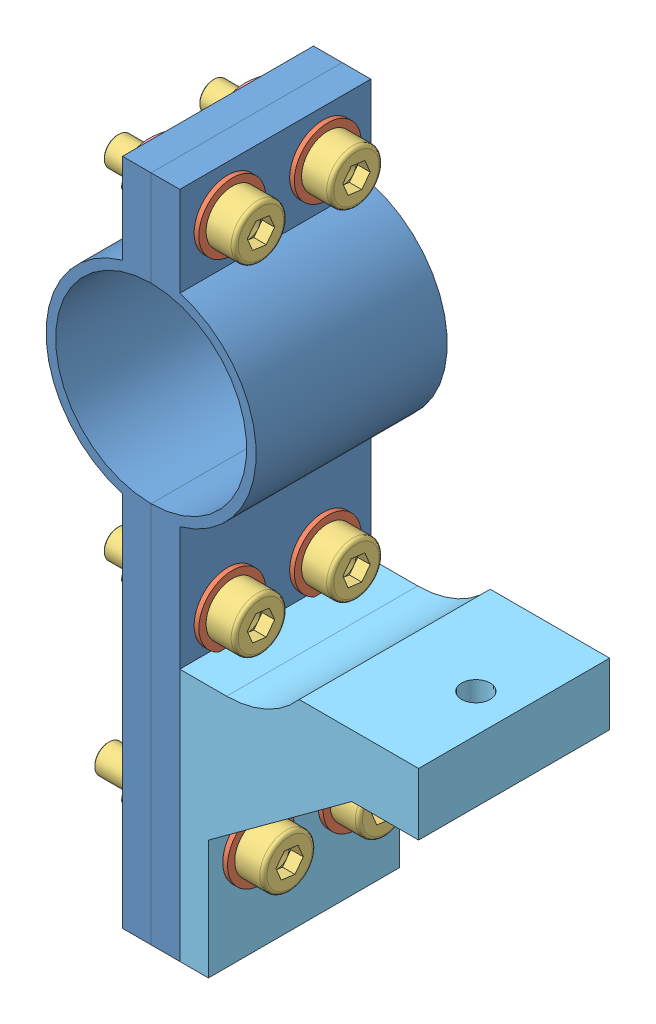
SolidWorks assembly 导轨夹具, configuration 默认. Lengths in mm.
Overall size (41 70 20).
22 component instances, 5 part files, 15 mates.
Components (placement in the parent):
- 小管夹具-1: 小管夹具 [默认] at (-12.5658 -21.1975 0) size (22 70 20)
  - 夹具-1: 夹具 [默认] at (55.615 31.0944 -10) size (11 70 20)
  - 夹具-2: 夹具 [默认] at (55.615 31.0944 10) x (-1 0 0) z (0 0 -1) size (11 70 20)
  - plain washers-n series-grade a gb-2: plain washers-n series-grade a gb [GB_FASTENER_WASHER_PWNA 3] at (59.115 46.3859 5) x (0 0 -1) z (1 0 0) size (7 7 0.5)
  - plain washers-n series-grade a gb-3: plain washers-n series-grade a gb [GB_FASTENER_WASHER_PWNA 3] at (59.115 46.3859 -5) x (0 0 -1) z (1 0 0) size (7 7 0.5)
  - plain washers-n series-grade a gb-4: plain washers-n series-grade a gb [GB_FASTENER_WASHER_PWNA 3] at (59.115 10.8029 -5) x (0 0 -1) z (1 0 0) size (7 7 0.5)
  - plain washers-n series-grade a gb-5: plain washers-n series-grade a gb [GB_FASTENER_WASHER_PWNA 3] at (59.115 10.8029 5) x (0 0 -1) z (1 0 0) size (7 7 0.5)
  - hexagon socket head cap screws gb-2: hexagon socket head cap screws gb [GB_FASTENER_SCREWS_HSHCS M3X12-N] at (62.115 10.8029 -5) x (-1 0 0) z (0 0.924225 0.381849) size (15 5.5 5.5)
  - hexagon socket head cap screws gb-3: hexagon socket head cap screws gb [GB_FASTENER_SCREWS_HSHCS M3X12-N] at (62.115 10.8029 5) x (-1 0 0) z (0 0.924225 0.381849) size (15 5.5 5.5)
  - hexagon socket head cap screws gb-4: hexagon socket head cap screws gb [GB_FASTENER_SCREWS_HSHCS M3X12-N] at (62.115 46.3859 -5) x (-1 0 0) z (0 0.924225 0.381849) size (15 5.5 5.5)
  - hexagon socket head cap screws gb-5: hexagon socket head cap screws gb [GB_FASTENER_SCREWS_HSHCS M3X12-N] at (62.115 46.3859 5) x (-1 0 0) z (0 0.924225 0.381849) size (15 5.5 5.5)
  - hex nuts, style 1-grades ab gb-2: hex nuts, style 1-grades ab gb [GB_FASTENER_NUT_SNAB1 M3-N] at (50.215 10.8029 -5) x (0 0 1) z (-1 0 0) size (6.35 5.5 2.4)
  - hex nuts, style 1-grades ab gb-3: hex nuts, style 1-grades ab gb [GB_FASTENER_NUT_SNAB1 M3-N] at (50.215 10.8029 5) x (0 0 1) z (-1 0 0) size (6.35 5.5 2.4)
  - hex nuts, style 1-grades ab gb-4: hex nuts, style 1-grades ab gb [GB_FASTENER_NUT_SNAB1 M3-N] at (50.215 46.3859 -5) x (0 0 1) z (-1 0 0) size (6.35 5.5 2.4)
  - hex nuts, style 1-grades ab gb-5: hex nuts, style 1-grades ab gb [GB_FASTENER_NUT_SNAB1 M3-N] at (50.215 46.3859 5) x (0 0 1) z (-1 0 0) size (6.35 5.5 2.4)
- 滑轨支架-1: 滑轨支架 [默认] at (49.0492 14.8969 -10) x (0 0 1) z (-1 0 0) size (20 30 27)
- plain washers-n series-grade a gb-2: plain washers-n series-grade a gb [GB_FASTENER_WASHER_PWNA 3] at (49.5492 -30.3946 5) x (0 0 -1) z (1 0 0) size (7 7 0.5)
- plain washers-n series-grade a gb-3: plain washers-n series-grade a gb [GB_FASTENER_WASHER_PWNA 3] at (49.5492 -30.3946 -5) x (0 0 -1) z (1 0 0) size (7 7 0.5)
- hexagon socket head cap screws gb-2: hexagon socket head cap screws gb [GB_FASTENER_SCREWS_HSHCS M3X16-N] at (52.5492 -30.3946 5) x (-1 0 0) z (0 0.924225 0.381849) size (19 5.5 5.5)
- hexagon socket head cap screws gb-3: hexagon socket head cap screws gb [GB_FASTENER_SCREWS_HSHCS M3X16-N] at (52.5492 -30.3946 -5) x (-1 0 0) z (0 0.924225 0.381849) size (19 5.5 5.5)
- hex nuts, style 1-grades ab gb-2: hex nuts, style 1-grades ab gb [GB_FASTENER_NUT_SNAB1 M3-N] at (37.6492 -30.3946 5) x (0 0 1) z (-1 0 0) size (6.35 5.5 2.4)
- hex nuts, style 1-grades ab gb-3: hex nuts, style 1-grades ab gb [GB_FASTENER_NUT_SNAB1 M3-N] at (37.6492 -30.3946 -5) x (0 0 1) z (-1 0 0) size (6.35 5.5 2.4)
Mates (geometry in assembly coordinates):
- 重合1: coincident anti-aligned: plane of 小管夹具-1/夹具-2 through (46.0492 9.8969 -10) normal (1 0 0); plane of 滑轨支架-1 through (46.0492 14.8969 -10) normal (-1 0 0)
- 同心1: concentric aligned: cylinder of 小管夹具-1/夹具-2 through (26.0492 -30.3946 5) axis (1 0 0) radius 1.5; cylinder of 滑轨支架-1 through (46.0492 -30.3946 5) axis (1 0 0) radius 2
- 同心2: concentric anti-aligned: cylinder of 小管夹具-1/夹具-1 through (60.0492 -30.3946 -5) axis (-1 0 0) radius 1.5; cylinder of 滑轨支架-1 through (46.0492 -30.3946 -5) axis (1 0 0) radius 2
- 同心3: concentric aligned: cylinder of 滑轨支架-1 through (46.0492 -30.3946 5) axis (1 0 0) radius 2; cylinder of plain washers-n series-grade a gb-2 through (49.0492 -30.3946 5) axis (1 0 0) radius 1.6
- 重合2: coincident anti-aligned: plane of 滑轨支架-1 through (49.0492 14.8969 -10) normal (1 0 0); plane of plain washers-n series-grade a gb-2 through (49.0492 -30.3946 5) normal (-1 0 0)
- 同心4: concentric aligned: cylinder of 滑轨支架-1 through (46.0492 -30.3946 -5) axis (1 0 0) radius 2; cylinder of plain washers-n series-grade a gb-3 through (49.0492 -30.3946 -5) axis (1 0 0) radius 1.6
- 重合3: coincident anti-aligned: plane of 滑轨支架-1 through (49.0492 14.8969 -10) normal (1 0 0); plane of plain washers-n series-grade a gb-3 through (49.0492 -30.3946 -5) normal (-1 0 0)
- 同心5: concentric aligned: cylinder of 滑轨支架-1 through (46.0492 -30.3946 5) axis (1 0 0) radius 2; cylinder of hexagon socket head cap screws gb-2 through (33.5492 -30.3946 5) axis (1 0 0) radius 1.5
- 重合4: coincident anti-aligned: plane of plain washers-n series-grade a gb-2 through (49.5492 -30.3946 5) normal (1 0 0); plane of hexagon socket head cap screws gb-2 through (49.5492 -30.3946 5) normal (-1 0 0)
- 同心6: concentric aligned: cylinder of 滑轨支架-1 through (46.0492 -30.3946 -5) axis (1 0 0) radius 2; cylinder of hexagon socket head cap screws gb-3 through (33.5492 -30.3946 -5) axis (1 0 0) radius 1.5
- 重合5: coincident anti-aligned: plane of plain washers-n series-grade a gb-3 through (49.5492 -30.3946 -5) normal (1 0 0); plane of hexagon socket head cap screws gb-3 through (49.5492 -30.3946 -5) normal (-1 0 0)
- 同心7: concentric anti-aligned: cylinder of hexagon socket head cap screws gb-2 through (33.5492 -30.3946 5) axis (1 0 0) radius 1.5; cone of hex nuts, style 1-grades ab gb-2 through (40.0492 -30.3946 5) axis (-1 0 0)
- 重合6: coincident anti-aligned: plane of 小管夹具-1/夹具-1 through (40.0492 9.8969 10) normal (-1 0 0); plane of hex nuts, style 1-grades ab gb-2 through (40.0492 -35.8946 5) normal (1 0 0)
- 同心8: concentric anti-aligned: cylinder of hexagon socket head cap screws gb-3 through (33.5492 -30.3946 -5) axis (1 0 0) radius 1.5; cone of hex nuts, style 1-grades ab gb-3 through (40.0492 -30.3946 -5) axis (-1 0 0)
- 重合7: coincident anti-aligned: plane of 小管夹具-1/夹具-1 through (40.0492 9.8969 10) normal (-1 0 0); plane of hex nuts, style 1-grades ab gb-3 through (40.0492 -35.8946 -5) normal (1 0 0)
